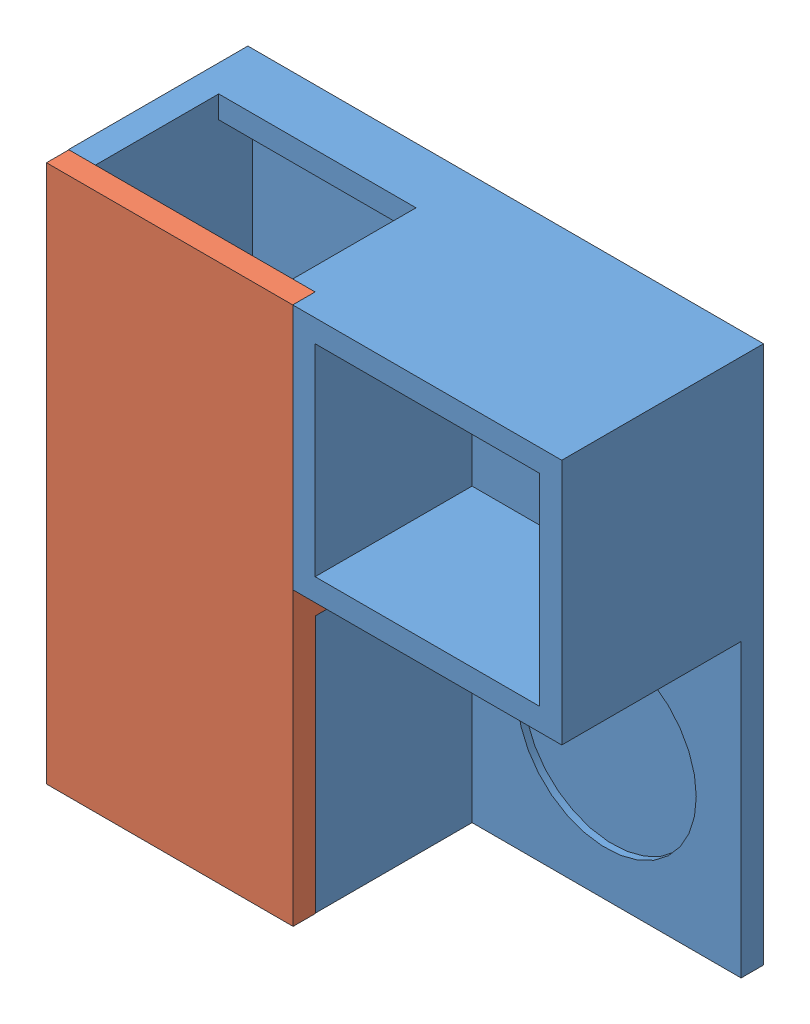
SolidWorks assembly Montagem2, configuration Valor predeterminado. Lengths in mm.
Overall size (230 240 90).
2 component instances, 2 part files, 3 mates.
Components (placement in the parent):
- caixaV2-1: caixaV2 [Valor predeterminado] at (-72.953 102.965 240) size (230 240 90)
- tampav2-1: tampav2 [Valor predeterminado] at (-206.6145 -80.6826 330) x (0 1 0) z (-1 0 0) size (240 20 110)
Mates (geometry in assembly coordinates):
- Paralelo1: parallel anti-aligned: plane of caixaV2-1 through (-72.953 102.965 320) normal (0 0 1); plane of tampav2-1 through (-206.6145 -80.6826 320) normal (0 0 -1)
- Coincidente4: coincident anti-aligned: plane of caixaV2-1 through (-220.1707 12.9889 310.0001) normal (0 -1 0); plane of tampav2-1 through (-232.0037 12.9889 310.0001) normal (0 1 0)
- Coincidente6: coincident anti-aligned: plane of caixaV2-1 through (-72.953 102.965 310.0001) normal (0 0 1); plane of tampav2-1 through (-206.6145 -80.6826 310.0001) normal (0 0 -1)
